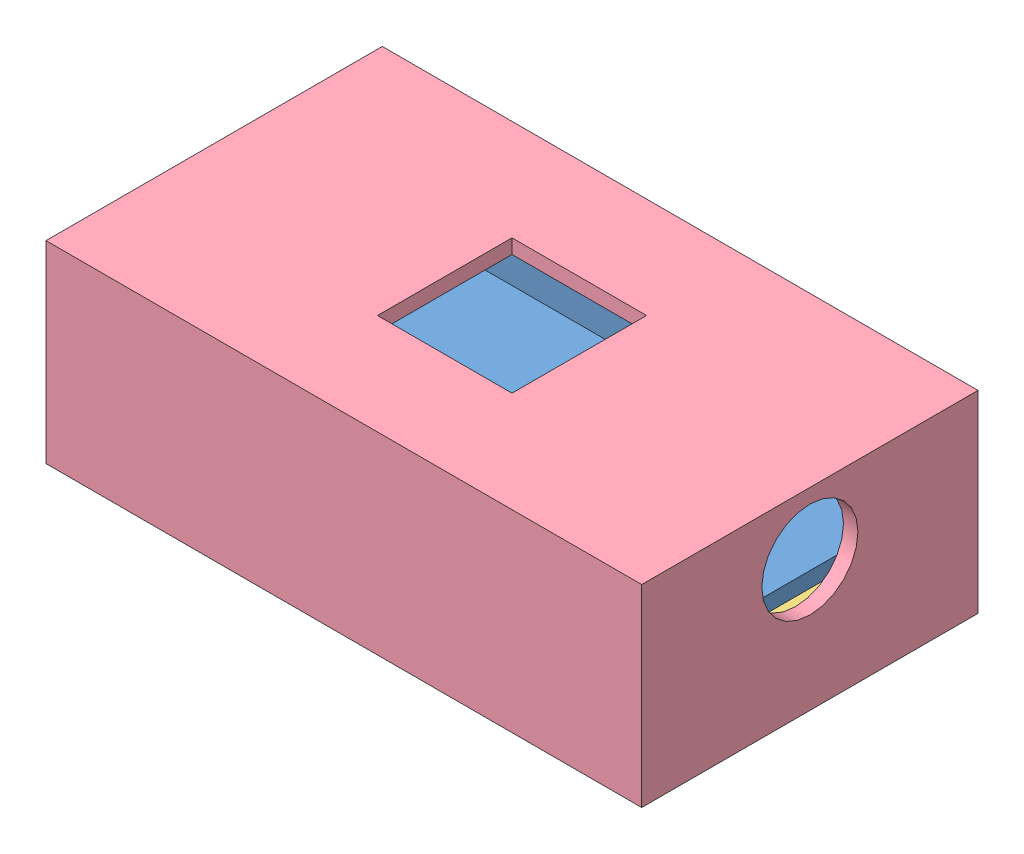
SolidWorks assembly 装配体3, configuration 默认. Lengths in mm.
Overall size (62 20.1 35).
7 component instances, 4 part files, 10 mates.
Components (placement in the parent):
- esp8266New-2: esp8266New [默认] at (-13.2603 -2.2228 59.048) x (1 0 0) z (0 0 -1) size (57 12.9 30.4)
- CopperPillar-1: CopperPillar [默认] at (-30.1605 -8.8228 44.7) x (1 0 0) z (0 1 0) size (5.31 4.63 8)
- CopperPillar-2: CopperPillar [默认] at (21.8395 -8.8228 44.7) x (1 0 0) z (0 1 0) size (5.31 4.63 8)
- CopperPillar-3: CopperPillar [默认] at (21.8395 -8.8228 69.3) x (1 0 0) z (0 1 0) size (5.31 4.63 8)
- CopperPillar-4: CopperPillar [默认] at (-30.1605 -8.8228 69.3) x (1 0 0) z (0 1 0) size (5.31 4.63 8)
- DiKe2-1: DiKe2 [默认] at (-8.0224 -12.3228 52.4657) size (59 3.5 32)
- ShangKe-1: ShangKe [默认] at (-7.1573 3.7772 61.7518) size (62 20.1 35)
Mates (geometry in assembly coordinates):
- 重合1: coincident anti-aligned: circle of esp8266New-2; plane of CopperPillar-1 through (-30.1605 -3.8228 44.7) normal (0 1 0)
- 重合2: coincident anti-aligned: plane of esp8266New-2 through (-13.2603 -3.8228 59.048) normal (0 -1 0); plane of CopperPillar-4 through (-30.1605 -3.8228 69.3) normal (0 1 0)
- 重合3: coincident anti-aligned: plane of esp8266New-2 through (-13.2603 -3.8228 59.048) normal (0 -1 0); plane of CopperPillar-2 through (21.8395 -3.8228 44.7) normal (0 1 0)
- 重合4: coincident anti-aligned: plane of esp8266New-2 through (-13.2603 -3.8228 59.048) normal (0 -1 0); plane of CopperPillar-3 through (21.8395 -3.8228 69.3) normal (0 1 0)
- 同心1: concentric aligned: circle of esp8266New-2; circle of CopperPillar-1
- 同心2: concentric aligned: circle of esp8266New-2; circle of CopperPillar-4
- 同心3: concentric aligned: circle of esp8266New-2; circle of CopperPillar-3
- 同心4: concentric aligned: circle of esp8266New-2; circle of CopperPillar-2
- 距离1: distance = 10 mm aligned: plane of esp8266New-2 through (-13.2603 -2.2228 59.048) normal (0 1 0); plane of ShangKe-1 through (-7.1573 7.7772 61.7518) normal (0 1 0)
- 重合15: coincident anti-aligned: plane of CopperPillar-1 through (-30.1605 -8.8228 44.7) normal (0 -1 0); plane of DiKe2-1 through (-30.1217 -8.8228 44.7) normal (0 1 0)
